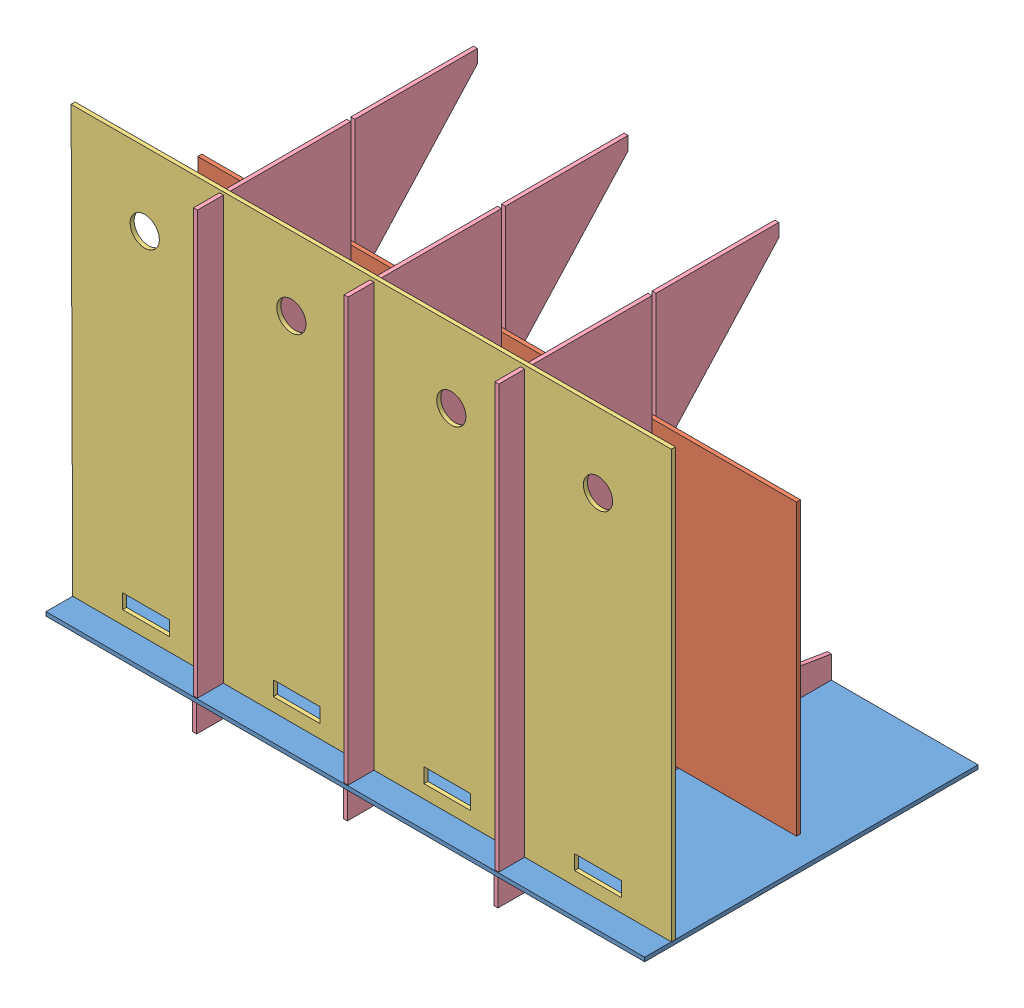
SolidWorks assembly assy, configuration Default. Lengths in mm.
Overall size (450.71 343 250).
6 component instances, 4 part files, 15 mates.
Components (placement in the parent):
- bawah-1: bawah [Default] at (126.1722 248.3626 356.9614) size (449 3 250)
- depan-1: depan [Default] at (75.098 379.7041 398.4466) size (449 217 3)
- dinding belakang-1: dinding belakang [Default] at (-37.364 570.2793 494.0163) size (450.17 340 3)
- dinding pinggir-1: dinding pinggir [Default] at (299.8037 518.2661 392.0163) size (3 340 250)
- dinding pinggir-2: dinding pinggir [Default] at (186.8037 518.2661 392.0163) size (3 340 250)
- dinding pinggir-3: dinding pinggir [Default] at (73.8037 518.2661 392.0163) size (3 340 250)
Mates (geometry in assembly coordinates):
- Coincident3: coincident anti-aligned: plane of bawah-1 through (299.8037 251.3626 392.0163) normal (0 0 -1); plane of dinding pinggir-1 through (302.8037 248.3626 392.0163) normal (0 0 1)
- Coincident4: coincident: line of bawah-1 through (302.8037 248.3626 267.0163) axis (0 0 1); plane of dinding pinggir-1 through (302.8037 518.2661 392.0163) normal (1 0 0)
- Coincident5: coincident: plane of bawah-1 through (126.1722 248.3626 356.9614) normal (0 -1 0); line of dinding pinggir-1 through (302.8037 248.3626 392.0163) axis (0 0 1)
- Parallel1: parallel aligned: plane of bawah-1 through (337.8037 248.3626 494.0163) normal (0 0 1); plane of dinding belakang-1 through (-37.364 570.2793 497.0163) normal (0 0 1)
- Coincident9: coincident: plane of bawah-1 through (337.8037 248.3626 494.0163) normal (0 0 1); line of dinding belakang-1 through (377.8037 231.3626 494.0163) axis (-1 0 0)
- Coincident10: coincident: line of bawah-1 through (337.8037 248.3626 494.0163) axis (0 0 1); plane of dinding belakang-1 through (337.8037 231.3626 497.0163) normal (-1 0 0)
- Coincident11: coincident: line of bawah-1 through (-36.1963 251.3626 517.0163) axis (1 0 0); plane of dinding belakang-1 through (412.8037 251.3626 497.0163) normal (0 -1 0)
- Coincident12: coincident anti-aligned: plane of depan-1 through (301.098 368.3626 401.4466) normal (0 -1 0); plane of dinding pinggir-1 through (302.8037 368.3626 398.4466) normal (0 1 0)
- Coincident13: coincident: plane of depan-1 through (75.098 379.7041 401.4466) normal (0 0 1); line of dinding pinggir-1 through (302.8037 368.3626 401.4466) axis (0 1 0)
- Coincident14: coincident: line of bawah-1 through (186.8037 251.3626 392.0163) axis (0 0 -1); plane of dinding pinggir-2 through (186.8037 518.2661 392.0163) normal (-1 0 0)
- Coincident15: coincident aligned: plane of bawah-1 through (76.8037 251.3626 267.0163) normal (0 0 -1); plane of dinding pinggir-2 through (189.8037 268.3626 267.0163) normal (0 0 -1)
- Coincident16: coincident aligned: plane of dinding pinggir-1 through (302.8037 568.3621 306.4466) normal (0 1 0); plane of dinding pinggir-2 through (189.8037 568.3621 306.4466) normal (0 1 0)
- Coincident17: coincident: line of bawah-1 through (73.8037 251.3626 392.0163) axis (0 0 -1); plane of dinding pinggir-3 through (73.8037 518.2661 392.0163) normal (-1 0 0)
- Coincident18: coincident aligned: plane of bawah-1 through (-36.1963 251.3626 267.0163) normal (0 0 -1); plane of dinding pinggir-3 through (76.8037 268.3626 267.0163) normal (0 0 -1)
- Coincident19: coincident aligned: plane of dinding pinggir-2 through (189.8037 568.3621 401.4466) normal (0 1 0); plane of dinding pinggir-3 through (76.8037 568.3621 401.4466) normal (0 1 0)
